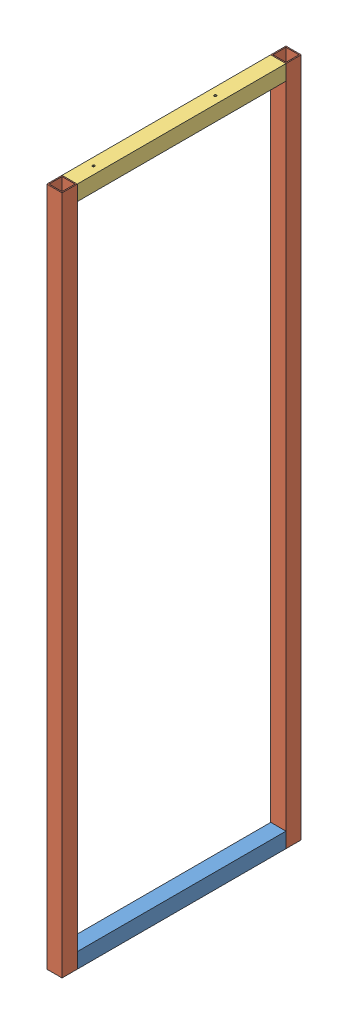
SolidWorks assembly GE-20309, configuration Default. Lengths in mm.
Overall size (44.45 1985.96 698.5).
4 component instances, 3 part files, 12 mates.
Components (placement in the parent):
- GE-20309-01-1: GE-20309-01 [Default] at (331.1866 322.2348 120.4204) size (44.45 44.45 609.6)
- GE-20309-02-1: GE-20309-02 [Default] at (331.1866 322.2348 774.4704) size (44.45 1985.96 44.45)
- GE-20309-02-2: GE-20309-02 [Default] at (331.1866 322.2348 120.4204) size (44.45 1985.96 44.45)
- GE-20309-03-1: GE-20309-03 [Default] at (331.1866 2263.7473 120.4204) size (44.45 44.45 609.6)
Mates (geometry in assembly coordinates):
- Coincident1: coincident anti-aligned: plane of GE-20309-01-1 through (331.1866 322.2348 120.4204) normal (0 0 -1); plane of GE-20309-02-2 through (331.1866 2308.1973 120.4204) normal (0 0 1)
- Coincident2: coincident aligned: plane of GE-20309-01-1 through (375.6366 322.2348 730.0204) normal (1 0 0); plane of GE-20309-02-2 through (375.6366 2308.1973 120.4204) normal (1 0 0)
- Coincident3: coincident aligned: plane of GE-20309-01-1 through (331.1866 322.2348 730.0204) normal (0 -1 0); plane of GE-20309-02-2 through (331.1866 322.2348 120.4204) normal (0 -1 0)
- Coincident4: coincident anti-aligned: plane of GE-20309-01-1 through (331.1866 322.2348 730.0204) normal (0 0 1); plane of GE-20309-02-1 through (331.1866 2308.1973 730.0204) normal (0 0 -1)
- Coincident5: coincident aligned: plane of GE-20309-01-1 through (375.6366 322.2348 730.0204) normal (1 0 0); plane of GE-20309-02-1 through (375.6366 2308.1973 774.4704) normal (1 0 0)
- Coincident6: coincident aligned: plane of GE-20309-01-1 through (331.1866 322.2348 730.0204) normal (0 -1 0); plane of GE-20309-02-1 through (331.1866 322.2348 774.4704) normal (0 -1 0)
- Coincident7: coincident anti-aligned: plane of leg_1-2 through (331.1866 2258.9848 120.4204) normal (0 0 -1); plane of GE-20309-02-2 through (331.1866 2308.1973 120.4204) normal (0 0 1)
- Coincident8: coincident aligned: plane of leg_1-2 through (375.6366 2258.9848 730.0204) normal (1 0 0); plane of GE-20309-02-2 through (375.6366 2308.1973 120.4204) normal (1 0 0)
- Coincident9: coincident aligned: plane of leg_1-2 through (331.1866 2303.4348 730.0204) normal (0 1 0); plane of GE-20309-02-2 through (331.1866 2308.1973 120.4204) normal (0 1 0)
- Coincident10: coincident aligned: plane of GE-20309-02-1 through (375.6366 2308.1973 774.4704) normal (1 0 0); plane of GE-20309-03-1 through (375.6366 2263.7473 730.0204) normal (1 0 0)
- Coincident11: coincident anti-aligned: plane of GE-20309-02-2 through (331.1866 2308.1973 120.4204) normal (0 0 1); plane of GE-20309-03-1 through (331.1866 2263.7473 120.4204) normal (0 0 -1)
- Coincident12: coincident aligned: plane of GE-20309-02-2 through (331.1866 2308.1973 120.4204) normal (0 1 0); plane of GE-20309-03-1 through (331.1866 2308.1973 730.0204) normal (0 1 0)
